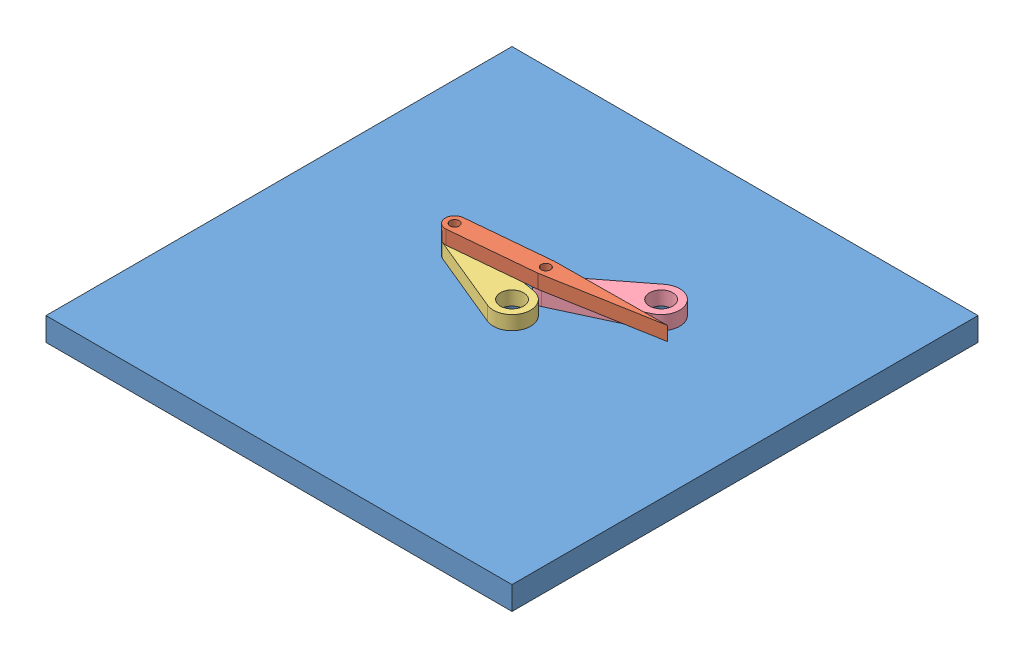
SolidWorks assembly all, configuration 默认. Lengths in mm.
Overall size (100 11 100).
4 component instances, 4 part files, 7 mates.
Components (placement in the parent):
- a-1: a [默认] at (-0.1873 -2.3619 0.4681) size (100 5 100)
- d-1: d [默认] at (-17.4844 5.6381 -4.5128) x (0.995755 0 -0.092042) z (0.092042 0 0.995755) size (44 3 4)
- c-1: c [默认] at (-0.1873 2.6381 0.4681) x (-0.960952 0 -0.276715) z (0.276715 0 -0.960952) size (24 3 8)
- b-1: b [默认] at (15.8127 2.6381 -15.5319) x (-0.854086 0 0.520132) z (-0.520132 0 -0.854086) size (24 3 8)
Mates (geometry in assembly coordinates):
- 同心1: concentric aligned: circle of a-1; circle of b-1
- 重合7: coincident anti-aligned: plane of a-1 through (-0.1873 2.6381 0.4681) normal (0 1 0); plane of b-1 through (-2.0378 2.6381 -17.8466) normal (0 -1 0)
- 同心2: concentric aligned: circle of a-1; circle of c-1
- 重合9: coincident anti-aligned: plane of a-1 through (-0.1873 2.6381 0.4681) normal (0 1 0); plane of c-1 through (-16.5031 2.6381 -7.1342) normal (0 -1 0)
- 同心3: concentric aligned: circle of d-1; circle of c-1
- 同心4: concentric aligned: circle of d-1; circle of b-1
- 重合12: coincident anti-aligned: plane of d-1 through (-2.0378 5.6381 -17.8466) normal (0 -1 0); plane of b-1 through (-2.0378 5.6381 -17.8466) normal (0 1 0)
